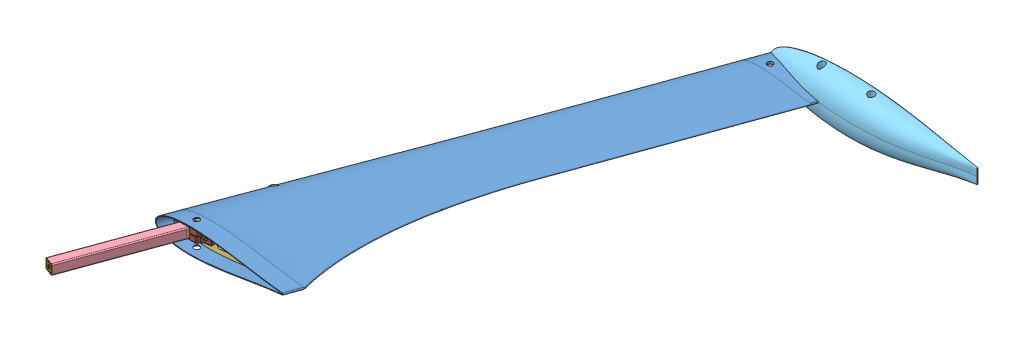
SolidWorks assembly Keel_Wide_Assembled, configuration Default. Lengths in mm.
Overall size (896.45 115.05 1266.37).
16 component instances, 11 part files, 47 mates.
Components (placement in the parent):
- Keel_outline_wide-1: Keel_outline_wide [Default] at (0 0 469.9) size (546.15 69.48 1040.39)
- Keel_streamline_rib_wide-1: Keel_streamline_rib_wide [Lightening] at (139.2796 0 -5.08) size (194.14 63.66 5.08)
- Keel_MasterRib_Wide-1: Keel_MasterRib_Wide [Default] at (-32.7627 0 467.6023) size (349.91 115.05 5.08)
- Keel_streamline_rib_wide-2: Keel_streamline_rib_wide [Default] at (311.2337 0 -477.52) size (194.14 63.66 5.08)
- Keel_Core-1: Keel_Core [Default] at (-78.4798 0 718.8662) x (0 1 0) z (-0.939693 0 -0.34202) size (22.81 1303.02 22.81)
- Keel_bulb_Wide-1: Keel_bulb_Wide [Default] at (332.2727 0 -526.3454) x (1 0 0) z (0 0 -1) size (475 64.66 57.39)
- Keel_Rib2_Wide-2: Keel_Rib2_Wide [Default] at (86.7876 0 152.4) size (209.67 68.75 5.08)
- Keel_streamline_rib_wide-3: Keel_streamline_rib_wide [Lightening] at (196.5976 0 -162.56) size (194.14 63.66 5.08)
- Keel_streamline_rib_wide-4: Keel_streamline_rib_wide [Lightening] at (253.9157 0 -320.04) size (194.14 63.66 5.08)
- Keel_bulb_Wide-2: Keel_bulb_Wide [RightHalf] at (332.2727 0 -526.3454) x (1 0 0) z (0 0 -1) size (475 64.66 57.39)
- Keel_Rib1_Wide-3: Keel_Rib1_Wide [Default] at (17.9514 0 310.1223) size (261.7 85.81 5.08)
- Keel_bulb_support-1: Keel_bulb_support [Default<As Machined>] at (374.7402 0 -526.3454) x (-1 0 0) z (0 1 0) size (250.76 51.07 20.14)
- Keel_Core_DeckPlug-1: Keel_Core_DeckPlug [Default] at (-65.962 -0.5461 682.8771) x (0 -1 0) z (-0.939693 0 -0.34202) size (19.05 38.1 19.05)
- 92196A554_18-8 STAINLESS STEEL SOCKET HEAD CAP SCREW-1: 92196A554_18-8 STAINLESS STEEL SOCKET HEAD CAP SCREW [92196A554] at (573.3061 42.545 -516.8204) x (-0.237247 0 -0.971449) z (0 1 0) size (9.53 9.53 83.33)
- Rib_Clamp-1: Rib_Clamp [Default] at (342.9837 0 -472.44) x (1 0 0) z (0 -1 0) size (194.14 45.41 63.66)
- Rib_Clamp-2: Rib_Clamp [Default] at (-1.0127 0 472.6823) x (1 0 0) z (0 -1 0) size (194.14 45.41 63.66)
Mates (geometry in assembly coordinates):
- Coincident50: coincident aligned: plane of Keel_outline_wide-1 through (0 0 0) normal (0 0 1); plane of Keel_streamline_rib_wide-1 through (139.2796 0 0) normal (0 0 1)
- Coincident5: coincident aligned: plane of Keel_outline_wide-1 through (0 0 469.9) normal (0 1 0); plane of Keel_streamline_rib_wide-1 through (139.2796 0 -5.08) normal (0 1 0)
- Coincident10: coincident aligned: plane of Keel_outline_wide-1 through (0 0 -477.52) normal (0 0 1); plane of Keel_streamline_rib_wide-2 through (311.2337 0 -477.52) normal (0 0 1)
- Coincident8: coincident aligned: plane of Keel_outline_wide-1 through (0 0 469.9) normal (0 1 0); plane of Keel_streamline_rib_wide-2 through (311.2337 0 -477.52) normal (0 1 0)
- Coincident32: coincident anti-aligned: plane of Keel_Rib2_Wide-2 through (86.7876 0 152.4) normal (0 0 -1); plane of assembly through (0 0 152.4) normal (0 0 1)
- Coincident34: coincident aligned: plane of Keel_MasterRib_Wide-1 through (-32.7627 0 467.6023) normal (0 1 0); plane of Keel_Rib2_Wide-2 through (86.7876 0 152.4) normal (0 1 0)
- Coincident36: coincident aligned: plane of Keel_MasterRib_Wide-1 through (-32.7627 0 467.6023) normal (0 1 0); plane of Keel_streamline_rib_wide-4 through (253.9157 0 -320.04) normal (0 1 0)
- Distance2: distance = 152.4 mm anti-aligned: plane of Keel_streamline_rib_wide-4 through (253.9157 0 -314.96) normal (0 0 1); plane of Keel_streamline_rib_wide-3 through (196.5976 0 -162.56) normal (0 0 -1)
- Coincident40: coincident aligned: plane of Keel_MasterRib_Wide-1 through (-32.7627 0 467.6023) normal (0 1 0); plane of Keel_streamline_rib_wide-3 through (196.5976 0 -162.56) normal (0 1 0)
- Distance3: distance = 152.4 mm anti-aligned: plane of Keel_streamline_rib_wide-3 through (196.5976 0 -157.48) normal (0 0 1); plane of Keel_streamline_rib_wide-1 through (139.2796 0 -5.08) normal (0 0 -1)
- Coincident41: coincident aligned: plane of Keel_MasterRib_Wide-1 through (-32.7627 0 467.6023) normal (0 1 0); plane of Keel_bulb_Wide-1 through (807.2527 0 -527.5989) normal (0 1 0)
- Coincident46: coincident anti-aligned: plane of Keel_bulb_Wide-1 through (807.2527 0 -527.5989) normal (0 1 0); plane of Keel_bulb_Wide-2 through (807.2527 0 -527.5989) normal (0 -1 0)
- Coincident67: coincident aligned: plane of Keel_MasterRib_Wide-1 through (-32.7627 0 467.6023) normal (0 1 0); plane of assembly through (0 0 0) normal (0 1 0)
- Coincident91: coincident aligned: plane of Keel_Rib1_Wide-3 through (17.9514 0 310.1223) normal (0 1 0); plane of assembly through (0 0 0) normal (0 1 0)
- Distance6: distance = 152.4 mm anti-aligned: plane of Keel_streamline_rib_wide-1 through (139.2796 0 0) normal (0 0 1); plane of Keel_Rib2_Wide-2 through (86.7876 0 152.4) normal (0 0 -1)
- Coincident94: coincident: line of Keel_outline_wide-1 through (0 0 469.9) axis (0.34202 0 -0.939693); plane of Keel_Core-1 through (356.4625 -11.4046 -509.4727) normal (-0.939693 0 -0.34202)
- Coincident102: coincident: line of Keel_outline_wide-1 through (0 0 469.9) axis (0 0 -1); plane of assembly
- Coincident103: coincident aligned: plane of Keel_MasterRib_Wide-1 through (-32.7627 0 467.6023) normal (0 1 0); plane of Keel_Core-1 through (-78.4798 0 718.8662) normal (0 1 0)
- Coincident123: coincident: plane of Keel_Core-1 through (356.4625 -11.4046 -509.4727) normal (-0.939693 0 -0.34202); moEndPointRef_w of Keel_Rib2_Wide-2
- Coincident124: coincident anti-aligned: plane of Rib_Clamp-2 through (-15.7531 -8.8646 513.1814) normal (0.939693 0 0.34202); plane of Keel_Core-1 through (356.4625 -11.4046 -509.4727) normal (-0.939693 0 -0.34202)
- Coincident125: coincident aligned: plane of Keel_streamline_rib_wide-1 through (139.2796 0 -5.08) normal (0 1 0); plane of Keel_MasterRib_Wide-1 through (-32.7627 0 467.6023) normal (0 1 0)
- Coincident126: coincident: plane of Keel_Core-1 through (356.4625 -11.4046 -509.4727) normal (-0.939693 0 -0.34202); line of Keel_streamline_rib_wide-3 through (228.3476 8.8646 -157.48) axis (0 -1 0)
- Coincident127: coincident: plane of Keel_Core-1 through (356.4625 -11.4046 -509.4727) normal (-0.939693 0 -0.34202); line of Keel_streamline_rib_wide-4 through (285.6657 8.8646 -314.96) axis (0 -1 0)
- Coincident128: coincident: line of Keel_streamline_rib_wide-2 through (342.9837 8.8646 -472.44) axis (0 -1 0); plane of Keel_Core-1 through (356.4625 -11.4046 -509.4727) normal (-0.939693 0 -0.34202)
- Coincident136: coincident: line of Keel_MasterRib_Wide-1 through (-1.0127 8.8646 472.6823) axis (0 -1 0); plane of Keel_Core-1 through (356.4625 -11.4046 -509.4727) normal (-0.939693 0 -0.34202)
- Distance9: distance = 38.1 mm anti-aligned: plane of Keel_MasterRib_Wide-1 through (-32.7627 0 467.6023) normal (0 0 -1); plane of Keel_outline_wide-1 through (245.6312 0.0002 505.7023) normal (0 0 1)
- Coincident140: coincident: plane of Keel_Core-1 through (356.4625 -11.4046 -509.4727) normal (-0.939693 0 -0.34202); line of Keel_Rib1_Wide-3 through (56.3054 8.8646 315.2023) axis (0 -1 0)
- Distance7: distance = 152.4 mm anti-aligned: plane of Keel_Rib1_Wide-3 through (17.9514 0 315.2023) normal (0 0 1); plane of Keel_MasterRib_Wide-1 through (-32.7627 0 467.6023) normal (0 0 -1)
- Distance8: distance = 250.0845 mm: line of Keel_Core-1 through (-67.7629 8.8646 722.7668) axis (0 -1 0); plane of Keel_MasterRib_Wide-1 through (-32.7627 0 472.6823) normal (0 0 1)
- Coincident142: coincident anti-aligned: plane of Keel_Core-1 through (357.7156 -10.0711 -509.0166) normal (0 1 0); plane of Keel_Core_DeckPlug-1 through (-87.9435 -10.0711 715.4217) normal (0 -1 0)
- Coincident143: coincident anti-aligned: plane of Keel_Core-1 through (357.7156 -10.0711 -509.0166) normal (0.939693 0 0.34202); plane of Keel_Core_DeckPlug-1 through (-87.9435 8.9789 715.4217) normal (-0.939693 0 -0.34202)
- Coincident144: coincident aligned: plane of Keel_Core-1 through (-78.4798 0 718.8662) normal (-0.34202 0 0.939693); plane of Keel_Core_DeckPlug-1 through (-78.9929 -0.5461 718.6794) normal (-0.34202 0 0.939693)
- Coincident145: coincident anti-aligned: plane of Keel_Core-1 through (357.7156 -10.0711 -509.0166) normal (0 1 0); plane of Keel_bulb_support-1 through (375.3316 -10.0711 -557.4163) normal (0 -1 0)
- Parallel1: parallel anti-aligned: plane of Keel_Core-1 through (357.7156 -10.0711 -509.0166) normal (0.939693 0 0.34202); plane of Keel_bulb_support-1 through (375.3316 -10.0711 -557.4163) normal (-0.939693 0 -0.34202)
- Concentric4: concentric anti-aligned: cylinder of Keel_Core-1 through (361.7498 11.4046 -490.6545) axis (0 1 0) radius 3.3782; cylinder of Keel_bulb_support-1 through (361.7498 -10.0711 -490.6545) axis (0 -1 0) radius 2.0193
- Coincident148: coincident anti-aligned: plane of Keel_bulb_Wide-1 through (374.7402 -0.5461 -526.3454) normal (0 0 1); plane of Keel_bulb_support-1 through (374.7402 0 -526.3454) normal (0 0 -1)
- Coincident149: coincident anti-aligned: plane of Keel_bulb_Wide-1 through (375.3316 -10.6172 -557.4163) normal (0.939693 0 0.34202); plane of Keel_bulb_support-1 through (375.3316 -10.0711 -557.4163) normal (-0.939693 0 -0.34202)
- Coincident150: coincident anti-aligned: plane of Keel_bulb_Wide-2 through (339.7295 -3.8735 -526.3454) normal (0 0 1); plane of Keel_bulb_support-1 through (374.7402 0 -526.3454) normal (0 0 -1)
- Coincident151: coincident anti-aligned: plane of Keel_bulb_Wide-2 through (375.3316 -10.6172 -557.4163) normal (0.939693 0 0.34202); plane of Keel_bulb_support-1 through (375.3316 -10.0711 -557.4163) normal (-0.939693 0 -0.34202)
- Concentric5: concentric anti-aligned: cylinder of Keel_bulb_Wide-1 through (573.3061 9.525 -516.8204) axis (0 -1 0) radius 3.3782; cylinder of 92196A554_18-8 STAINLESS STEEL SOCKET HEAD CAP SCREW-1 through (573.3061 -33.655 -516.8204) axis (0 1 0) radius 3.175
- Coincident153: coincident anti-aligned: plane of Keel_bulb_Wide-1 through (573.3061 -33.655 -516.8204) normal (0 -1 0); plane of 92196A554_18-8 STAINLESS STEEL SOCKET HEAD CAP SCREW-1 through (573.3061 -33.655 -516.8204) normal (0 1 0)
- Coincident154: coincident anti-aligned: plane of Keel_Core-1 through (356.4625 11.4046 -509.4727) normal (0 1 0); plane of Rib_Clamp-1 through (330.7832 11.4046 -431.9409) normal (0 -1 0)
- Coincident156: coincident anti-aligned: plane of Keel_Core-1 through (356.4625 -11.4046 -509.4727) normal (-0.939693 0 -0.34202); plane of Rib_Clamp-1 through (328.2432 -8.8646 -431.9409) normal (0.939693 0 0.34202)
- Coincident157: coincident anti-aligned: plane of Keel_Core-1 through (356.4625 -11.4046 -509.4727) normal (-0.939693 0 -0.34202); plane of Rib_Clamp-2 through (-15.7531 -8.8646 513.1814) normal (0.939693 0 0.34202)
- Coincident158: coincident anti-aligned: plane of Keel_MasterRib_Wide-1 through (-32.7627 0 472.6823) normal (0 0 1); plane of Rib_Clamp-2 through (-1.0127 0 472.6823) normal (0 0 -1)
- Coincident159: coincident anti-aligned: plane of Keel_Core-1 through (356.4625 11.4046 -509.4727) normal (0 1 0); plane of Rib_Clamp-2 through (-13.2131 11.4046 513.1814) normal (0 -1 0)
- Coincident160: coincident anti-aligned: plane of Keel_streamline_rib_wide-2 through (311.2337 0 -472.44) normal (0 0 1); plane of Rib_Clamp-1 through (342.9837 0 -472.44) normal (0 0 -1)
